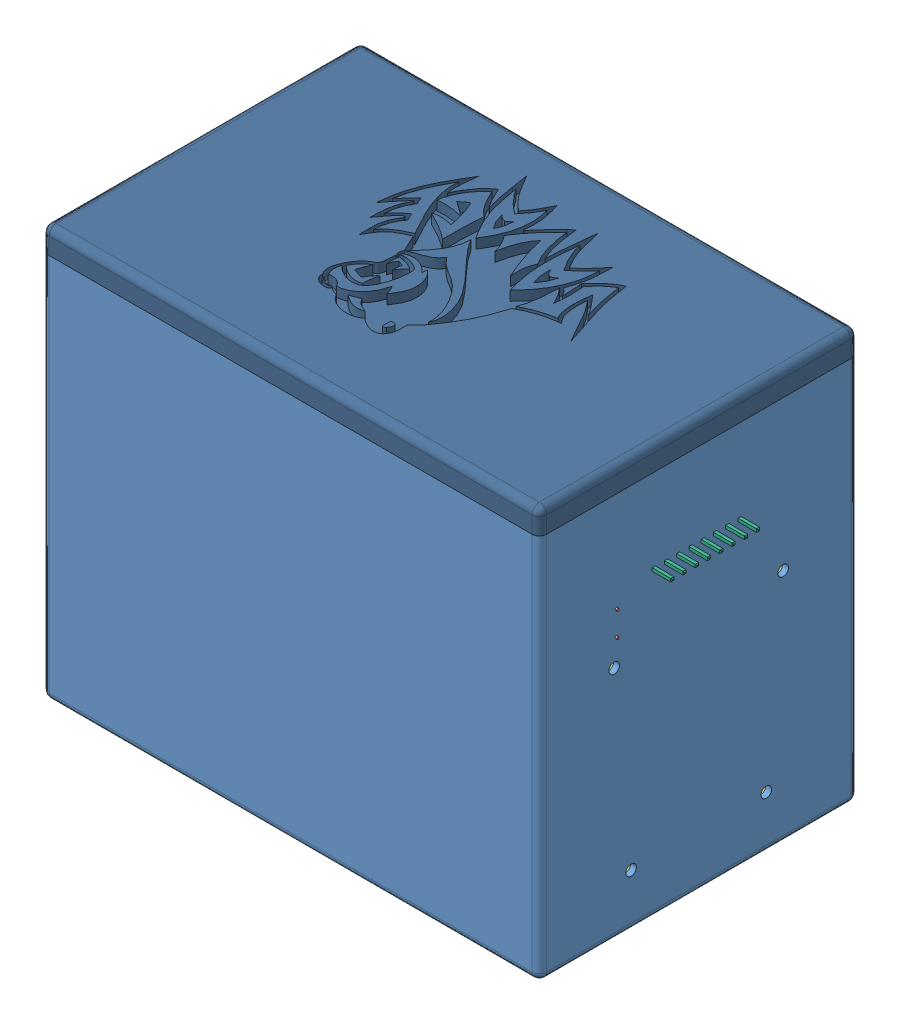
SolidWorks assembly rfid_assembly, configuration Default. Lengths in mm.
Overall size (108.4 85 68.2).
28 component instances, 10 part files, 7 mates.
Components (placement in the parent):
- rfid_bottom-1: rfid_bottom [Default] at (-113.405 42.4425 79.3574) size (103 80 66)
- ArduinoUno-1: ArduinoUno [Default] at (-108.406 49.0925 140.3515) x (-0.000425 0 1) z (-1 0 -0.000425) size (53.34 15.25 74.93)
- User Library-RFID-1: User Library-RFID [Default] at (47.845 76.6713 108.7014) x (0 0 1) z (-1 0 0) size (40 60 11.54)
  - User Library-RFID_Part1-1: User Library-RFID_Part1 [Default] at (-16.3439 30.7712 59.45) size (40 60 2)
  - User Library-RFID_Part10-1: User Library-RFID_Part10 [Default] at (20.709 20.1029 60.45) x (0 1 0) z (0 0 1) size (10.67 3.05 5.63)
  - User Library-RFID_User Library-S-PWSON-N12-1: User Library-RFID_User Library-S-PWSON-N12 [Default] at (4.1233 20.047 60.45) x (1 0 0) z (0 -1 0) size (3 0.8 3)
  - User Library-RFID_User Library-Header_Male_8Pin-1: User Library-RFID_User Library-Header_Male_8Pin [Default] at (12.9823 28.5305 62.74) x (-1 0 0) z (0 0 -1) size (20.32 2.49 11.54)
  - User Library-RFID_User Library-SMD Ceramic Capacitors_0603 (1608)_CH-1: User Library-RFID_User Library-SMD Ceramic Capacitors_0603 (1608)_CH [Default] at (-3.9959 5.9247 60.9127) size (1.72 0.91 0.98)
  - User Library-RFID_User Library-SMD Ceramic Capacitors_0603 (1608)_CH-2: User Library-RFID_User Library-SMD Ceramic Capacitors_0603 (1608)_CH [Default] at (-1.0806 5.9034 60.9127) size (1.72 0.91 0.98)
  - User Library-RFID_User Library-SMD Ceramic Capacitors_0603 (1608)_CH-3: User Library-RFID_User Library-SMD Ceramic Capacitors_0603 (1608)_CH [Default] at (2.2282 5.9089 60.9127) size (1.72 0.91 0.98)
  - User Library-RFID_User Library-SMD Ceramic Capacitors_0603 (1608)_CH-4: User Library-RFID_User Library-SMD Ceramic Capacitors_0603 (1608)_CH [Default] at (5.214 5.921 60.9127) size (1.72 0.91 0.98)
  - User Library-RFID_User Library-SMD Ceramic Capacitors_0603 (1608)_CH-5: User Library-RFID_User Library-SMD Ceramic Capacitors_0603 (1608)_CH [Default] at (8.193 5.9188 60.9127) size (1.72 0.91 0.98)
  - User Library-RFID_User Library-SMD Ceramic Capacitors_0603 (1608)_CH-6: User Library-RFID_User Library-SMD Ceramic Capacitors_0603 (1608)_CH [Default] at (11.3855 5.9271 60.9127) size (1.72 0.91 0.98)
  - User Library-RFID_User Library-SMD Ceramic Capacitors_0603 (1608)_CH-7: User Library-RFID_User Library-SMD Ceramic Capacitors_0603 (1608)_CH [Default] at (16.3593 23.3789 60.9127) size (1.72 0.91 0.98)
  - User Library-RFID_User Library-SMD Ceramic Capacitors_0603 (1608)_CH-8: User Library-RFID_User Library-SMD Ceramic Capacitors_0603 (1608)_CH [Default] at (16.3593 21.3117 60.9127) size (1.72 0.91 0.98)
  - User Library-RFID_User Library-SMD Ceramic Capacitors_0603 (1608)_CH-9: User Library-RFID_User Library-SMD Ceramic Capacitors_0603 (1608)_CH [Default] at (13.4136 25.6528 60.9127) size (1.72 0.91 0.98)
  - User Library-RFID_User Library-SMD Ceramic Capacitors_0603 (1608)_CH-10: User Library-RFID_User Library-SMD Ceramic Capacitors_0603 (1608)_CH [Default] at (13.517 19.0895 60.9127) size (1.72 0.91 0.98)
  - User Library-RFID_Part8-1: User Library-RFID_Part8 [Default] at (13.517 23.4826 60.704) size (1.6 0.81 0.51)
  - User Library-RFID_Part8-2: User Library-RFID_Part8 [Default] at (13.517 21.3121 60.704) size (1.6 0.81 0.51)
  - User Library-RFID_User Library-SMD Ceramic Capacitors_0603 (1608)_CH-11: User Library-RFID_User Library-SMD Ceramic Capacitors_0603 (1608)_CH [Default] at (-5.0547 25.4542 60.9127) size (1.72 0.91 0.98)
  - User Library-RFID_User Library-SMD Ceramic Capacitors_0603 (1608)_CH-12: User Library-RFID_User Library-SMD Ceramic Capacitors_0603 (1608)_CH [Default] at (-5.0547 21.4355 60.9127) size (1.72 0.91 0.98)
  - User Library-RFID_User Library-SMD Ceramic Capacitors_0603 (1608)_CH-13: User Library-RFID_User Library-SMD Ceramic Capacitors_0603 (1608)_CH [Default] at (-5.0547 19.367 60.9127) size (1.72 0.91 0.98)
  - User Library-RFID_Part8-3: User Library-RFID_Part8 [Default] at (-5.0547 23.3861 60.704) size (1.6 0.81 0.51)
  - User Library-RFID_Part8-4: User Library-RFID_Part8 [Default] at (-10.0418 25.4159 60.704) size (1.6 0.81 0.51)
  - User Library-RFID_Part8-5: User Library-RFID_Part8 [Default] at (-10.0625 23.4569 60.704) size (1.6 0.81 0.51)
  - User Library-RFID_Part8-6: User Library-RFID_Part8 [Default] at (-10.0541 27.4204 60.704) size (1.6 0.81 0.51)
- RSI1602-00.stp-2: RSI1602-00.stp [Default] at (-61.3628 93.5641 90.7591) x (-0.999889 -0.014867 0) z (0 0 -1) size (80.01 36.01 10.64)
- rfid_top-1: rfid_top [Default] at (-113.405 127.4425 79.3574) size (103 10 66)
Mates (geometry in assembly coordinates):
- Concentric6: concentric aligned: circle of rfid_bottom-1; circle of arduino uno-1
- Coincident2: coincident anti-aligned: plane of rfid_bottom-1 through (-113.405 47.4425 79.3574) normal (0 1 0); plane of arduino uno-1 through (-108.406 47.4425 140.3515) normal (0 -1 0)
- Concentric14: concentric anti-aligned: circle of rfid_bottom-1; circle of User Library-RFID-1/User Library-RFID_Part1-1
- Coincident4: coincident anti-aligned: plane of rfid_bottom-1 through (-11.605 122.4425 79.3574) normal (-1 0 0); plane of User Library-RFID-1/User Library-RFID_Part1-1 through (-11.605 107.4425 92.3574) normal (1 0 0)
- Coincident15: coincident anti-aligned: plane of rfid_bottom-1 through (-113.405 122.4425 79.3574) normal (0 1 0); plane of rfid_top-1 through (-113.405 122.4425 79.3574) normal (0 -1 0)
- Coincident17: coincident aligned: plane of rfid_bottom-1 through (-10.405 122.4425 79.3574) normal (1 0 0); plane of rfid_top-1 through (-10.405 122.4425 79.3574) normal (1 0 0)
- Coincident18: coincident aligned: plane of rfid_bottom-1 through (-113.405 122.4425 79.3574) normal (0 0 -1); plane of rfid_top-1 through (-113.405 122.4425 79.3574) normal (0 0 -1)
